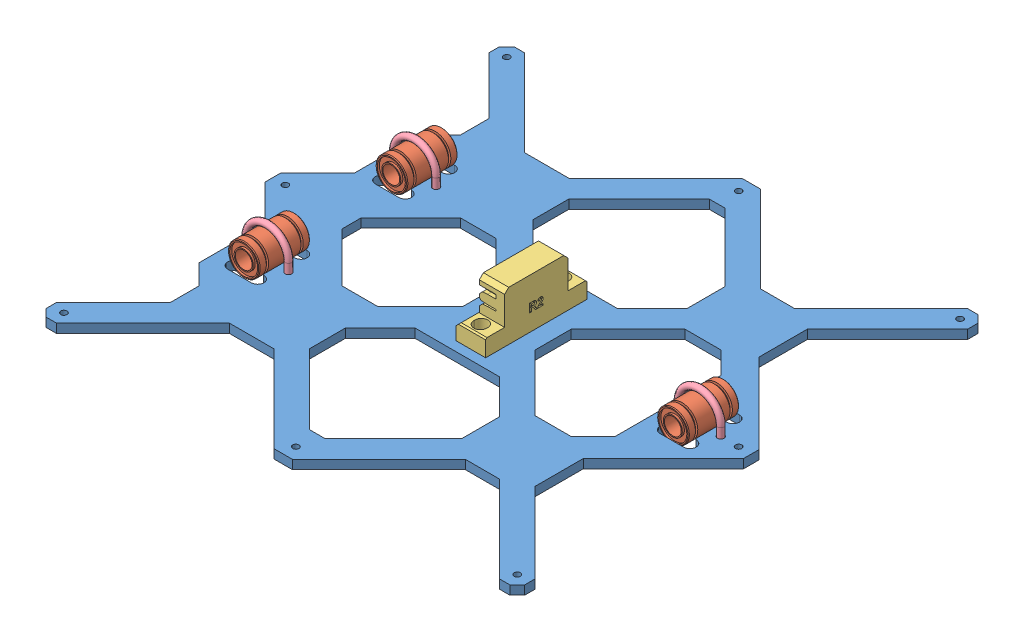
SolidWorks assembly Frog Assembly, configuration Default. Lengths in mm.
Overall size (227 34.1 222).
8 component instances, 4 part files, 21 mates.
Components (placement in the parent):
- i3 MK3 Frog-1: i3 MK3 Frog [Default] at (-100.0918 124.8902 356.7011) size (227 4.25 222)
- LM8UU-1: LM8UU [Default] at (166.4082 134.7303 172.4511) x (0 0 -1) z (0.49499 0.868899 0) size (24 15 15)
- LM8UU-2: LM8UU [Default] at (-3.5918 134.7303 205.9511) x (0 0 -1) z (0.957162 -0.289554 0) size (24 15 15)
- LM8UU-3: LM8UU [Default] at (-3.5918 134.7303 135.9511) x (0 0 -1) z (-0.936768 -0.349951 0) size (24 15 15)
- y-belt-holder(R2)-1: y-belt-holder(R2) [Default] at (88.4082 141.6402 171.2011) x (0 -1 0) z (-1 0 0) size (23.5 48 14)
- U Bolt-1: U Bolt [Default] at (166.4082 118.7303 171.7011) size (23.09 26.7 3.46)
- U Bolt-2: U Bolt [Default] at (-3.5918 118.7303 136.7011) size (23.09 26.7 3.46)
- U Bolt-3: U Bolt [Default] at (-3.5918 118.7303 206.7011) size (23.09 26.7 3.46)
Mates (geometry in assembly coordinates):
- Tangent1: tangent: line of i3 MK3 Frog-1 through (161.4082 129.1402 164.9511) axis (0 0 1); cylinder of LM8UU-1 through (166.4082 134.7303 218.1406) axis (0 0 1) radius 7.5
- Tangent2: tangent: line of i3 MK3 Frog-1 through (171.4082 129.1402 164.9511) axis (0 0 1); cylinder of LM8UU-1 through (166.4082 134.7303 218.1406) axis (0 0 1) radius 7.5
- Distance1: distance = 2 mm anti-aligned: plane of LM8UU-1 through (166.4082 134.7303 160.4511) normal (0 0 -1); plane of i3 MK3 Frog-1 through (-100.0918 129.1402 158.4511) normal (0 0 1)
- Tangent3: tangent: line of i3 MK3 Frog-1 through (1.4082 129.1402 199.9511) axis (0 0 1); cylinder of LM8UU-2 through (-3.5918 134.7303 251.6406) axis (0 0 1) radius 7.5
- Tangent4: tangent: line of i3 MK3 Frog-1 through (-8.5918 129.1402 199.9511) axis (0 0 1); cylinder of LM8UU-2 through (-3.5918 134.7303 251.6406) axis (0 0 1) radius 7.5
- Distance2: distance = 2 mm anti-aligned: plane of LM8UU-2 through (-3.5918 134.7303 217.9511) normal (0 0 1); plane of i3 MK3 Frog-1 through (-100.0918 129.1402 219.9511) normal (0 0 -1)
- Tangent5: tangent: line of i3 MK3 Frog-1 through (1.4082 129.1402 129.9511) axis (0 0 1); cylinder of LM8UU-3 through (-3.5918 134.7303 181.6406) axis (0 0 1) radius 7.5
- Tangent7: tangent: line of i3 MK3 Frog-1 through (-8.5918 129.1402 129.9511) axis (0 0 1); cylinder of LM8UU-3 through (-3.5918 134.7303 181.6406) axis (0 0 1) radius 7.5
- Distance3: distance = 2 mm anti-aligned: plane of LM8UU-3 through (-3.5918 134.7303 147.9511) normal (0 0 1); plane of i3 MK3 Frog-1 through (-100.0918 129.1402 149.9511) normal (0 0 -1)
- Coincident1: coincident anti-aligned: plane of i3 MK3 Frog-1 through (-100.0918 129.1402 356.7011) normal (0 1 0); plane of y-belt-holder(R2)-1 through (74.4082 129.1402 147.2011) normal (0 -1 0)
- Concentric1: concentric aligned: cylinder of i3 MK3 Frog-1 through (81.4082 129.1402 152.2011) axis (0 -1 0) radius 1.5; cylinder of y-belt-holder(R2)-1 through (81.4082 138.1402 152.2011) axis (0 -1 0) radius 3.1
- Parallel1: parallel aligned: plane of i3 MK3 Frog-1 through (61.9082 129.1402 356.7011) normal (-1 0 0); plane of y-belt-holder(R2)-1 through (74.4082 137.1402 147.2011) normal (-1 0 0)
- Concentric3: concentric anti-aligned: circle of i3 MK3 Frog-1; cylinder of U Bolt-1 through (156.4082 118.7303 171.7011) axis (0 -1 0) radius 1.5
- Concentric4: concentric aligned: circle of i3 MK3 Frog-1; cylinder of U Bolt-1 through (176.4082 103.7303 171.7011) axis (0 1 0) radius 1.5
- Concentric5: concentric anti-aligned: cylinder of i3 MK3 Frog-1 through (6.4082 129.1402 206.7011) axis (0 -1 0) radius 1.6; cylinder of U Bolt-3 through (6.6029 113.1835 195.6832) axis (0 1 0) radius 1.5
- Concentric6: concentric anti-aligned: circle of i3 MK3 Frog-1; cylinder of U Bolt-3 through (-13.3971 128.1835 195.6832) axis (0 -1 0) radius 1.5
- Concentric7: concentric anti-aligned: cylinder of i3 MK3 Frog-1 through (6.4082 129.1402 136.7011) axis (0 -1 0) radius 1.6; cylinder of U Bolt-2 through (5.5917 247.4793 260.6522) axis (0 1 0) radius 1.5
- Concentric8: concentric anti-aligned: circle of i3 MK3 Frog-1; cylinder of U Bolt-2 through (-14.4083 262.4793 260.6522) axis (0 -1 0) radius 1.5
- Tangent10: tangent aligned: cylinder of LM8UU-1 through (166.4082 134.7303 218.1406) axis (0 0 1) radius 7.5; plane of U Bolt-1 through (166.4082 127.2303 171.7011) normal (0 1 0)
- Tangent11: tangent aligned: cylinder of LM8UU-3 through (-3.5918 134.7303 181.6406) axis (0 0 1) radius 7.5; plane of U Bolt-2 through (-3.5918 142.2303 136.7011) normal (0 1 0)
- Tangent12: tangent aligned: cylinder of LM8UU-2 through (-3.5918 134.7303 251.6406) axis (0 0 1) radius 7.5; plane of U Bolt-3 through (-3.5918 142.2303 206.7011) normal (0 1 0)
